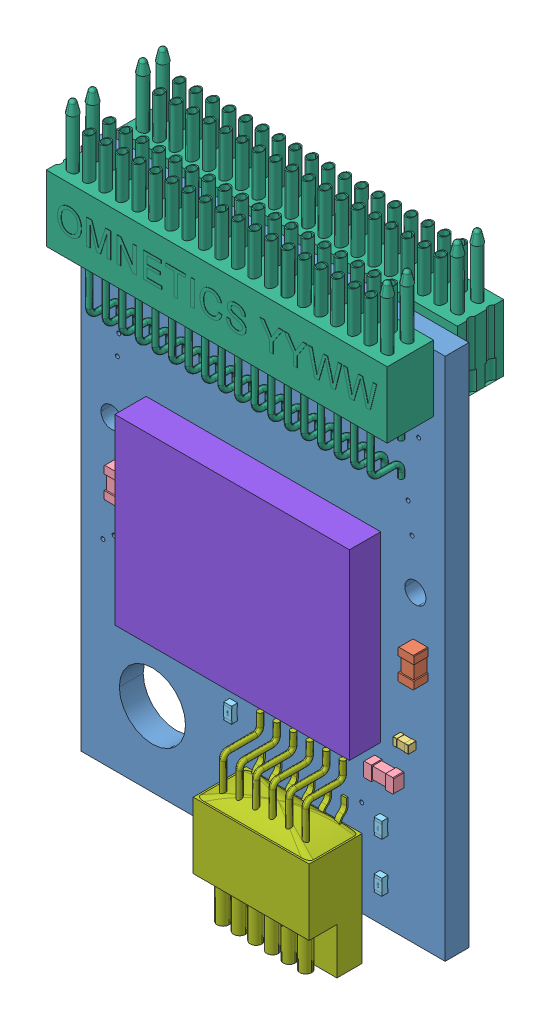
SolidWorks assembly RHD2164_headstage_bga.STEP, configuration Default. Lengths in mm.
Overall size (13.97 24.45 4.89).
12 component instances, 8 part files, 0 mates.
Components (placement in the parent):
- RHD2164_headstage_bga_PCB.STEP-1: RHD2164_headstage_bga_PCB.STEP [Default] at origin size (13.97 20.1 0.91)
- 0402c_2320560.STEP-1: 0402c_2320560.STEP [Default] at (13.0175 9.525 0.9144) x (0 1 0) z (0 0 1) size (1.15 0.6 0.55)
- 0201c_0201.STEP-1: 0201c_0201.STEP [Default] at (12.5603 6.6167 1.0644) size (0.6 0.3 0.3)
- 0402r_1430758.STEP-1: 0402r_1430758.STEP [Default] at (1.5621 9.779 0.9144) x (0 1 0) z (0 0 1) size (1.15 0.55 0.4)
- 0402r_1430758.STEP-2: 0402r_1430758.STEP [Default] at (11.8128 5.2256 0.9144) x (-1 0 0) z (0 0 1) size (1.15 0.55 0.4)
- 0201r_0201.STEP-1: 0201r_0201.STEP [Default] at (5.8532 4.3049 1.0294) x (-1 0 0) z (0 1 0) size (0.3 0.23 0.6)
- 0201r_0201.STEP-2: 0201r_0201.STEP [Default] at (11.6205 1.4732 1.0294) x (1 0 0) z (0 -1 0) size (0.3 0.23 0.6)
- 0201r_0201.STEP-3: 0201r_0201.STEP [Default] at (11.6205 3.3655 1.0294) x (-1 0 0) z (0 1 0) size (0.3 0.23 0.6)
- A79025-001.STEP-1: A79025-001.STEP [Default] at (5.715 19.1516 2.6924) size (13.14 7.45 2.1)
- A79025-001.STEP-2: A79025-001.STEP [Default] at (8.255 19.1516 -1.778) x (-1 0 0) z (0 0 -1) size (13.14 7.45 2.1)
- A79623-001.STEP-1: A79623-001.STEP [Default] at (8.5598 2.6543 0.9144) x (1 0 0) z (0 -1 0) size (4.45 2.05 6.53)
- RHD2164_bga.STEP-1: RHD2164_bga.STEP [Default] at (6.9977 9.5377 0.9144) size (9 7 1.2)
